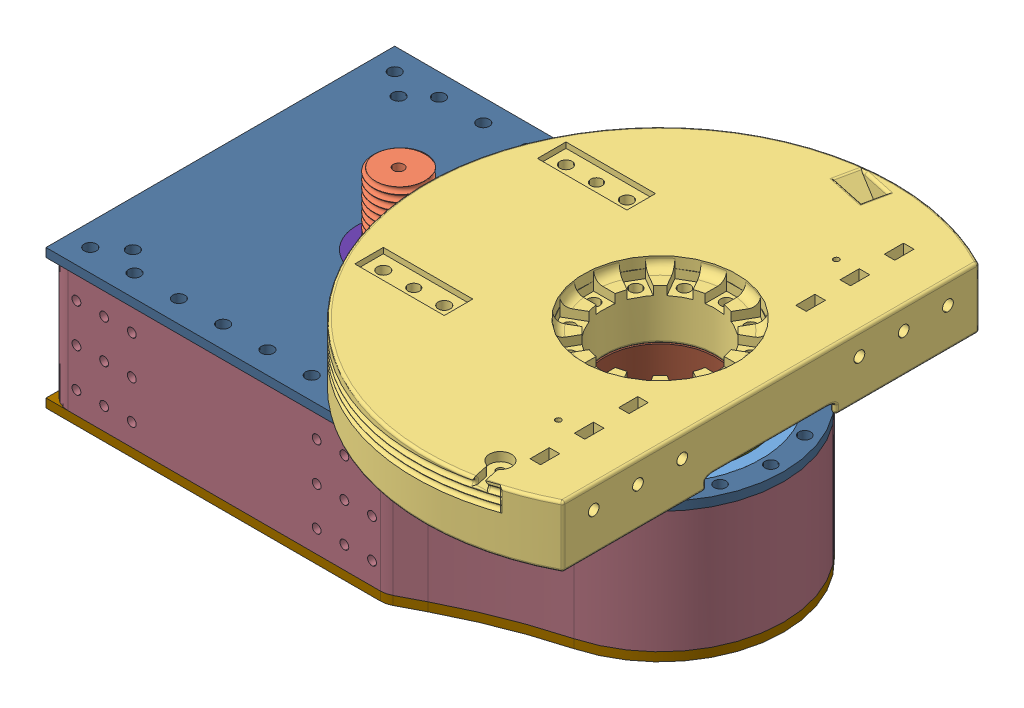
SolidWorks assembly shouler  joint, configuration Default. Lengths in mm.
Overall size (201.82 71.09 161.21).
23 component instances, 19 part files, 30 mates.
Components (placement in the parent):
- 0 Dimensions-1: 0 Dimensions [Default] at (-25.4 117.5088 0) x (-1 0 0) z (0 1 0) size (179.79 135 536.98) (hidden)
- Bearing 45_58_7mm-1: Bearing 45_58_7mm [Default] at (0 33.8775 0) x (1 0 0) z (0 1 0) size (58 58 7)
- Bearing 45_58_7mm-2: Bearing 45_58_7mm [Default] at (0 -0.11 0) x (1 0 0) z (0 1 0) size (58 58 7)
- small roller-1: small roller [Default] at (-75 49.065 0) x (0 0 1) z (-1 0 0) size (39.69 31.56 39.69)
- Big Cap Stan^shouler  joint-1: Big Cap Stan^shouler  joint [Default] at origin size (145.71 17.73 161.21) (virtual)
  - big roller-1: big roller [Default] at (0 49.065 0) x (-0.965911 0 0.258873) z (-0.258873 0 -0.965911) size (114.33 17.73 136.26)
  - Hall Indicating Magnet-1: Hall Indicating Magnet [Default] at (10.6828 41.8588 -39.8686) size (6.35 3.17 6.35)
  - Hall Indicating Magnet-2: Hall Indicating Magnet [Default] at (10.6828 41.8588 39.8686) size (6.35 3.17 6.35)
- Motor Assem-1: Motor Assem [Default] at (-75 14.125 0) x (0 0 1) z (-1 0 0) size (129.63 44.53 129.63)
  - 9225 160kv-1: 9225 160kv [Default] at (0 -18.055 0) x (0.707107 0 0.707107) z (-0.707107 0 0.707107) size (91.66 44.53 91.66)
  - Encoder Magnet-1: Encoder Magnet [Default] at (0 -19.6425 0) size (6.35 3.17 6.35)
  - Magnut hex puck-1: Magnut hex puck [Default] at (0 -18.055 0) x (0.707107 0 0.707107) z (-0.707107 0 0.707107) size (22.91 4.76 22.91)
  - encoder final board-1: encoder final board [Default] at (0 -23.0237 0) x (0 0 -1) z (1 0 0) size (25 2.95 25)
- Bottom Plate^shouler  joint-1: Bottom Plate^shouler  joint [Default] at origin size (161.47 2.5 100) (virtual)
- Top Plate^shouler  joint-1: Top Plate^shouler  joint [Default] at origin size (161.47 2.5 100) (virtual)
- Pivot^shouler  joint-1: Pivot^shouler  joint [Default] at origin size (50.08 43.88 50.08) (virtual)
- Pivot Washer^shouler  joint-1: Pivot Washer^shouler  joint [Default] at (0 -3.61 0) x (-1 0 0) z (0 -1 0) size (48.18 48.18 1.59) (virtual)
- Pivot Center Standoff^shouler  joint-1: Pivot Center Standoff^shouler  joint [Default] at origin size (161.47 34.88 100) (virtual)
- Encoder Mount^shouler  joint-1: Encoder Mount^shouler  joint [Default] at origin size (36.86 7.19 42.55) (virtual)
- Encoder Clamp^shouler  joint-1: Encoder Clamp^shouler  joint [Default] at origin size (17.14 1.59 42.55) (virtual)
- Pivot Top Spacer ^shouler  joint-1: Pivot Top Spacer ^shouler  joint [Default] at origin size (51.35 2.89 51.35) (virtual)
- Bearing 15_24_5mm-1: Bearing 15_24_5mm [Default] at (-75 34.8775 0) size (24 5 24)
- Hall Sensor Mount Stubby-1: Hall Sensor Mount Stubby [Default] at (-41.275 34.8775 0) x (0 0 1) z (-1 0 0) size (23.81 6.23 7.94)
Mates (geometry in assembly coordinates):
- Concentric1: concentric anti-aligned: cylinder of Bearing 45_58_7mm-1 through (0 37.3775 0) axis (0 -1 0) radius 22.5
- Concentric2: concentric anti-aligned: cylinder of Bearing 45_58_7mm-2 through (0 3.39 0) axis (0 -1 0) radius 22.5
- Coincident8: coincident anti-aligned: plane of Bearing 45_58_7mm-2 through (0 -0.11 0) normal (0 0 -1)
- Coincident9: coincident aligned: plane of Bearing 45_58_7mm-1 through (0 33.8775 0) normal (1 0 0)
- Coincident14: coincident anti-aligned: plane of Motor Assem-1/9225 160kv-1 through (-81.8236 0 6.8236) normal (0 -1 0)
- Coincident15: coincident: line of Motor Assem-1 through (-75 36.4765 0) axis (0 -1 0)
- Coincident16: coincident: point of small roller-1; line of Motor Assem-1 through (-75 36.4765 0) axis (0 -1 0)
- Coincident17: coincident anti-aligned: plane of small roller-1 through (-75 28.25 0) normal (0 -1 0); plane of Motor Assem-1/9225 160kv-1 through (-97.981 28.25 22.981) normal (0 1 0)
- Concentric6: concentric aligned: cylinder of small roller-1 through (-64.0398 30.79 -10.9602) axis (0 1 0) radius 1.7; cylinder of Motor Assem-1/9225 160kv-1 through (-64.0398 28.25 -10.9602) axis (0 1 0) radius 1.25
- Coincident18: coincident aligned: plane of Motor Assem-1 through (-75 14.125 0) normal (0 0 1)
- Coincident19: coincident anti-aligned: plane of Bearing 45_58_7mm-2 through (0 0 0) normal (0 1 0); plane of Motor Assem-1/9225 160kv-1 through (-80.9598 0 6.8236) normal (0 -1 0)
- Distance1: distance = 26.9875 mm anti-aligned: plane of Bearing 45_58_7mm-2 through (0 3.39 0) normal (0 1 0); plane of Bearing 45_58_7mm-1 through (0 30.3775 0) normal (0 -1 0)
- InPlace1: in place: plane of ? through (-15.875 -5.1975 0) normal (0 -1 0); plane of ? through (0 -5.1975 0) normal (0 -1 0); moOrthogonalPlaneRef_w of ? through (-15.875 -5.1975 0) normal (0 -1 0); plane of ? through (0 -5.1975 0) normal (0 0 -1); plane of ? through (-15.875 -5.1975 0) normal (0 -1 0); plane of ? through (0 -5.1975 0) normal (-1 0 0); plane of ? through (-15.875 -3.61 0) normal (0 -1 0); unknown of Pivot Washer^shouler  joint-1
- Coincident22: coincident aligned: plane of Pivot^shouler  joint-1; plane of Pivot Washer^shouler  joint-1
- Coincident23: coincident aligned: moOrthogonalPlaneRef_w of Pivot^shouler  joint-1 through (0 -3.61 0) normal (0 0 -1); plane of Pivot Washer^shouler  joint-1 through (0 -3.61 0) normal (0 0 -1)
- Coincident24: coincident anti-aligned: moOrthogonalPlaneRef_w of Pivot^shouler  joint-1 through (0 -3.61 0) normal (1 0 0); plane of Pivot Washer^shouler  joint-1 through (0 -3.61 0) normal (-1 0 0)
- Coincident20: coincident aligned: circle of small roller-1; plane of Bearing 15_24_5mm-1 through (-75 32.3775 0) normal (0 -1 0)
- Concentric7: concentric aligned: cylinder of Bearing 15_24_5mm-1 through (-75 37.3775 0) axis (0 -1 0) radius 7.5
- Coincident21: coincident aligned: plane of Bearing 15_24_5mm-1 through (-75 34.8775 0) normal (0 0 1)
- Coincident22: coincident anti-aligned: line of 0 Dimensions-1 through (50.8 0 117.5088) axis (0 0 -1)
- Coincident23: coincident aligned: plane of 0 Dimensions-1 through (-25.4 117.5088 0) normal (0 0 1)
- Coincident25: coincident aligned: plane of Bearing 45_58_7mm-1 through (0 37.3775 0) normal (0 1 0); plane of Top Plate^shouler  joint-1 through (-30.2345 37.3775 43.65) normal (0 1 0)
- Concentric8: concentric anti-aligned: cylinder of Top Plate^shouler  joint-1 through (-41.275 34.8775 0) axis (0 1 0) radius 3.9688; cylinder of Hall Sensor Mount-1 through (-41.275 37.2587 0) axis (0 -1 0) radius 3.9688
- Coincident26: coincident: plane of Hall Sensor Mount-1 through (-41.275 34.8775 0) normal (0 0 1)
- Coincident27: coincident anti-aligned: plane of Top Plate^shouler  joint-1 through (-30.2345 34.8775 43.65) normal (0 -1 0); plane of Hall Sensor Mount-1 through (-41.275 34.8775 -7.9375) normal (0 1 0)
- Coincident31: coincident anti-aligned: line of Big Cap Stan^shouler  joint-1/big roller-1 through (110 0 104.065) axis (0 0 -1)
- Coincident32: coincident aligned: plane of small roller-1 through (-75 49.065 0) normal (0 1 0); plane of Big Cap Stan^shouler  joint-1/big roller-1 through (0 49.065 0) normal (0 1 0)
- Tangent2: tangent anti-aligned: cylinder of small roller-1 through (-75 57.815 0) axis (0 -1 0) radius 7.5; cylinder of Big Cap Stan^shouler  joint-1/big roller-1 through (0 57.065 0) axis (0 -1 0) radius 67.5
- Parallel2: parallel aligned: plane of Big Cap Stan^shouler  joint-1/big roller-1 through (11.29 49.065 0) normal (1 0 0)
- Coincident33: coincident anti-aligned: plane of Big Cap Stan^shouler  joint-1/big roller-1 through (33.4638 57.8588 57.5246) normal (0 1 0); plane of 0 Dimensions-1 through (-25.4 57.8588 0) normal (0 -1 0)
